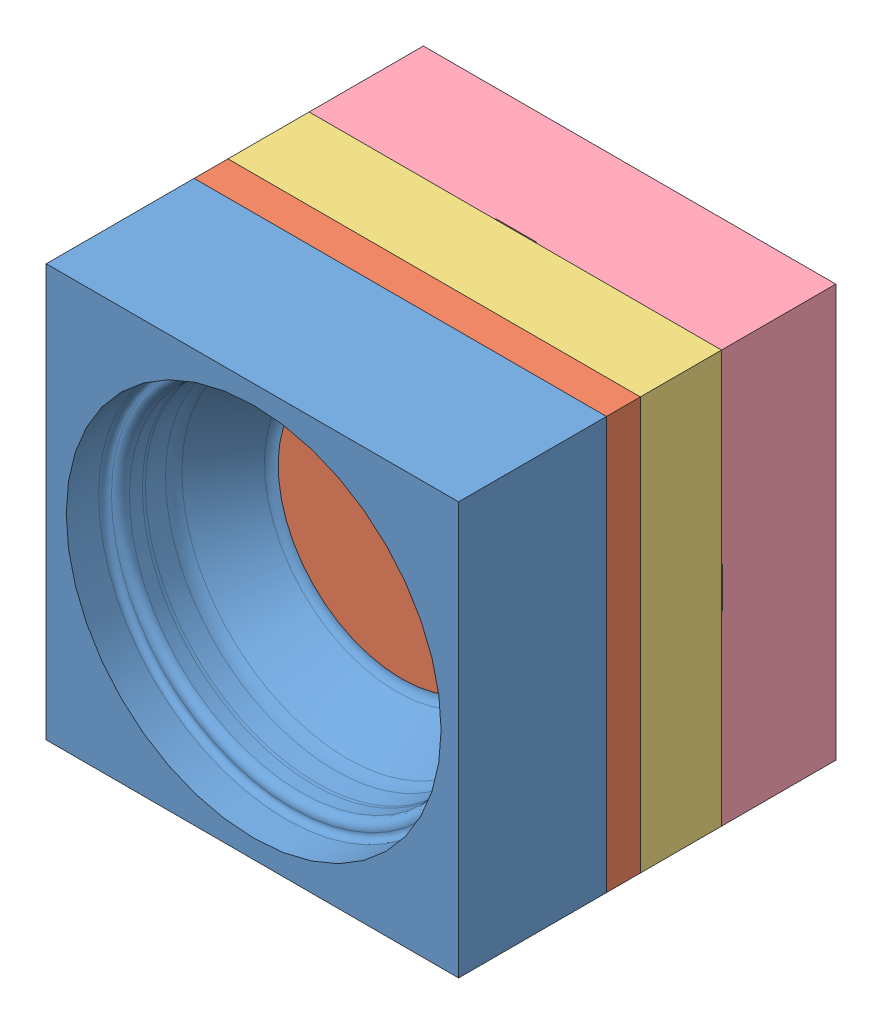
SolidWorks assembly mold assembly R1, configuration Default. Lengths in mm.
Overall size (383.81 304.8 305.71).
4 component instances, 4 part files, 9 mates.
Components (placement in the parent):
- Mold2-1: Mold2 [Default] at (231.412 170.3771 -104.5115) size (304.8 304.8 109.32)
- mold5-1: mold5 [Default] at (231.412 170.3771 -2.3785) size (304.8 304.8 25)
- Mold 3-1: Mold 3 [Default] at (231.412 170.3771 -129.5115) size (304.8 304.8 60)
- Mold4-1: Mold4 [Default] at (231.412 170.3771 -129.5115) size (304.8 304.8 84.45)
Mates (geometry in assembly coordinates):
- Coincident1: coincident: plane of Mold2-1 through (231.412 170.3771 22.6215) normal (0 0 -1); plane of mold5-1 through (231.412 170.3771 22.6215) normal (0 0 1)
- Coincident2: coincident: plane of Mold2-1 through (383.812 322.7771 124.0885) normal (1 0 0); plane of mold5-1 through (383.812 17.9771 22.6215) normal (1 0 0)
- Coincident3: coincident: plane of Mold2-1 through (383.812 322.7771 124.0885) normal (0 1 0); plane of mold5-1 through (79.012 322.7771 22.6215) normal (0 1 0)
- Coincident4: coincident: plane of mold5-1 through (231.412 170.3771 -2.3785) normal (0 0 -1); plane of Mold 3-1 through (231.412 170.3771 -2.3785) normal (0 0 1)
- Coincident5: coincident: plane of mold5-1 through (383.812 17.9771 22.6215) normal (1 0 0); plane of Mold 3-1 through (383.812 322.7771 99.0885) normal (1 0 0)
- Coincident6: coincident: plane of mold5-1 through (79.012 322.7771 22.6215) normal (0 1 0); plane of Mold 3-1 through (383.812 322.7771 99.0885) normal (0 1 0)
- Coincident7: coincident: plane of Mold 3-1 through (231.412 170.3771 -62.3785) normal (0 0 -1); plane of Mold4-1 through (231.412 170.3771 -62.3785) normal (0 0 1)
- Coincident8: coincident: plane of Mold 3-1 through (383.812 322.7771 99.0885) normal (1 0 0); plane of Mold4-1 through (383.812 322.7771 99.0885) normal (1 0 0)
- Coincident9: coincident: plane of Mold 3-1 through (383.812 322.7771 99.0885) normal (0 1 0); plane of Mold4-1 through (383.812 322.7771 99.0885) normal (0 1 0)
